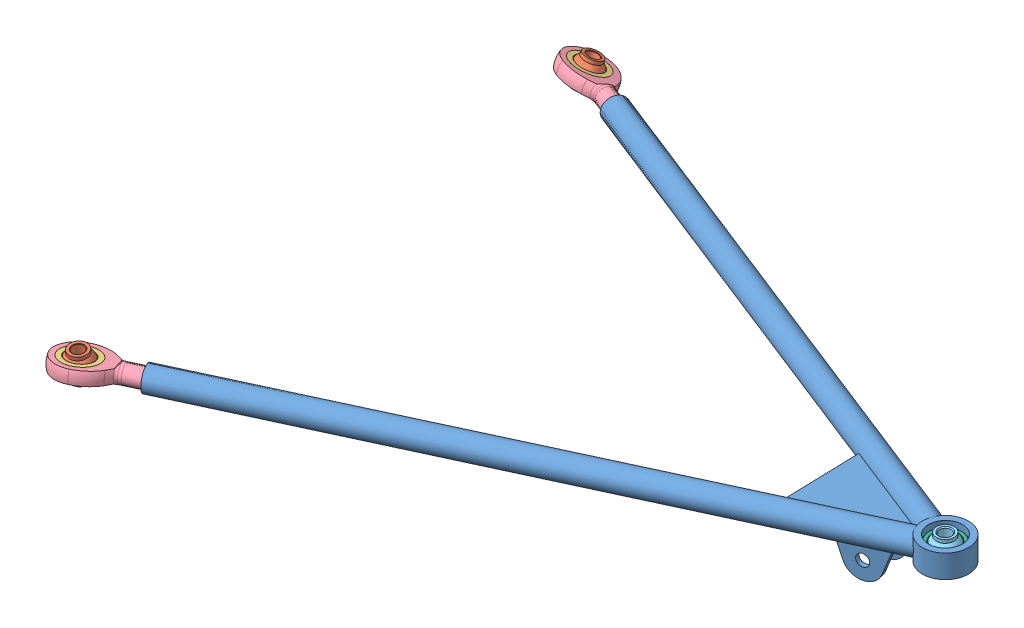
SolidWorks assembly Front Top Wishbone, configuration Default. Lengths in mm.
Overall size (359.08 48.54 328.78).
12 component instances, 6 part files, 6 mates.
Components (placement in the parent):
- Front Top Wishbone-1: Front Top Wishbone [Default<As Machined>] at (308.1951 167.2782 369.2129) size (316.29 35.42 269.21)
- HXAM-4T Rod End-1: HXAM-4T Rod End [Default] at (-17.9558 167.2782 240.7181) x (0.897746 0.034217 0.439183) z (-0.419021 0.373943 0.827398) size (64.66 26.81 33.4) (flexible)
  - HXAM-4T Ball-1: HXAM-4T Ball [Default] at (0 0 -49.2252) size (15.06 15.06 15.06)
  - HXAM-4T Sleeve-1: HXAM-4T Sleeve [Default] at (49.0403 -0.0911 -4.2615) x (-0.086591 -0.024106 -0.995952) z (-0.996244 0.001851 0.086572) size (19.53 6.73 19.53)
  - HXAM-4T Housing-1: HXAM-4T Housing [Default] at (49.0403 -0.0911 -4.2615) x (-0.086591 -0.024106 -0.995952) z (-0.996244 0.001851 0.086572) size (27.48 26.04 62.51)
- HXAM-4T Rod End-2: HXAM-4T Rod End [Default] at (-17.9558 167.2782 520.1181) x (0.996925 -0.002239 -0.078328) z (0.077686 -0.10264 0.99168) size (69.58 34.39 53.09) (flexible)
  - HXAM-4T Ball-1: HXAM-4T Ball [Default] at (0 0 -49.2252) size (15.06 15.06 15.06)
  - HXAM-4T Sleeve-1: HXAM-4T Sleeve [Default] at (46.1567 -1.6532 -17.0279) x (0.342331 0.260993 0.902603) z (-0.937664 0.033584 0.345918) size (19.53 6.73 19.53)
  - HXAM-4T Housing-1: HXAM-4T Housing [Default] at (46.1567 -1.6532 -17.0279) x (0.342331 0.260993 0.902603) z (-0.937664 0.033584 0.345918) size (27.48 26.04 62.51)
- HAB-4T Bearing-1: HAB-4T Bearing [Default] at (308.1951 167.2782 369.2129) x (0.999975 -0.007095 -0.000077) z (-0.000077 -0.021669 0.999765) size (19.45 15.06 19.55) (flexible)
  - HAB-4T Ball-1: HAB-4T Ball [Default] at origin size (15.06 15.06 15.06)
  - HAB-4T Cup-1: HAB-4T Cup [Default] x (0.999428 0.006373 -0.033204) z (0.033057 0.021893 0.999214) size (18.8 6.48 18.8)
Mates (geometry in assembly coordinates):
- Concentric2: concentric anti-aligned: cylinder of Front Top Wishbone-1 through (308.1951 174.0559 369.2129) axis (0 -1 0) radius 9.3345; cylinder of HAB-4T Bearing-1/HAB-4T Cup-1 through (308.1951 167.2782 369.2129) axis (0 1 0) radius 9.398
- Coincident1: coincident anti-aligned: plane of Front Top Wishbone-1 through (308.1951 164.0397 369.2129) normal (0 1 0); plane of HAB-4T Bearing-1/HAB-4T Cup-1 through (308.1951 164.0397 369.2129) normal (0 -1 0)
- Concentric3: concentric anti-aligned: cylinder of Front Top Wishbone-1 through (308.1951 167.2782 369.2129) axis (-0.907563 0 0.419916) radius 6.35; cylinder of HXAM-4T Rod End-2/HXAM-4T Housing-1 through (12.7507 167.2782 505.9106) axis (0.907563 0 -0.419916) radius 4.7625
- Concentric4: concentric aligned: cylinder of Front Top Wishbone-1 through (7.9095 167.2782 250.9084) axis (0.930398 0 0.366552) radius 6.35; cylinder of ? through (13.5233 167.2782 253.1201) axis (0.930398 0 0.366552) radius 4.7625
- Coincident2: coincident: point of Front Top Wishbone-1; point of HXAM-4T Rod End-1/HXAM-4T Ball-1
- Coincident3: coincident: point of Front Top Wishbone-1; point of HXAM-4T Rod End-2/HXAM-4T Ball-1
